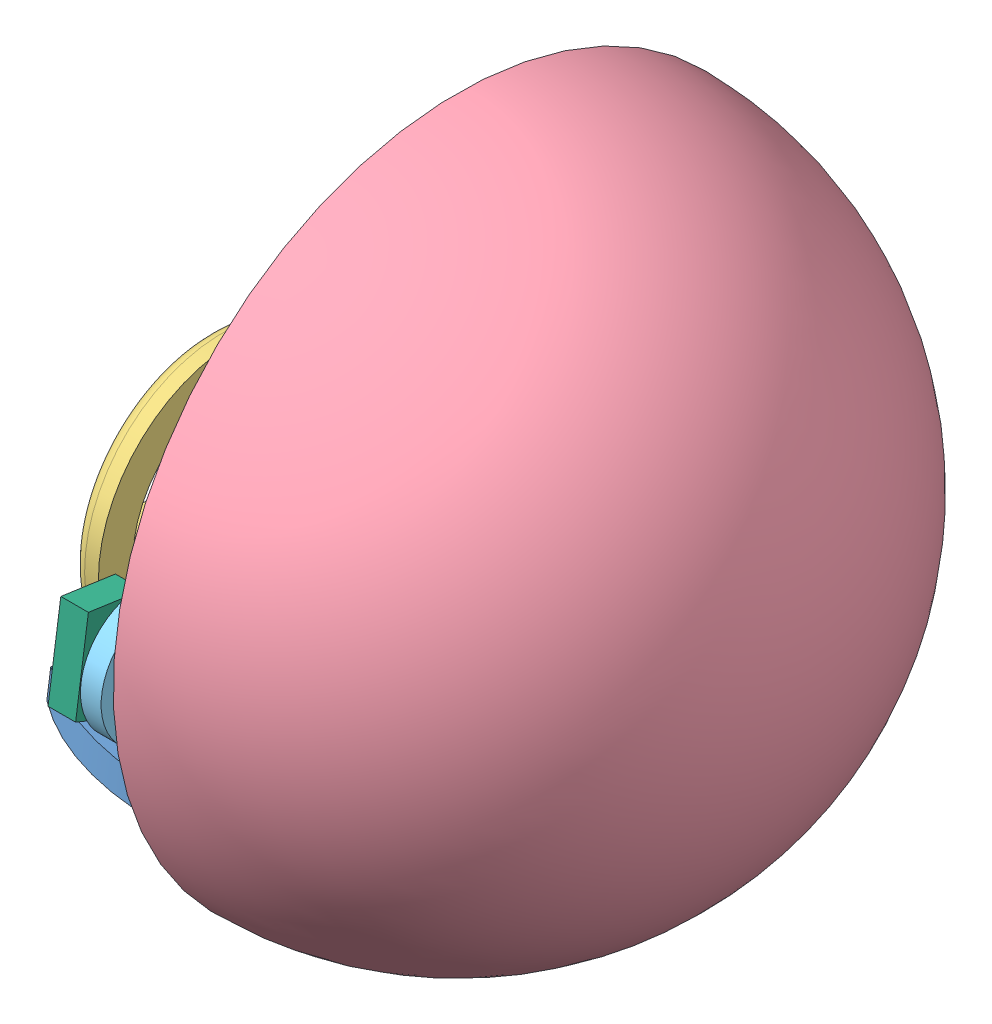
SolidWorks assembly Main, configuration Default. Lengths in mm.
Overall size (84.01 140.15 140.15).
13 component instances, 6 part files, 31 mates.
Components (placement in the parent):
- Base-1: Base [Default] at (37.3353 -161.0107 -76.7882) x (1 0 0) z (0 0.142722 0.989763) size (50 4 80)
- Motor Mount-1: Motor Mount [Default] at (15.3353 -157.0516 -77.3591) x (0 -0.142722 -0.989763) z (1 0 0) size (15.67 16 4)
- Motor Mount-2: Motor Mount [Default] at (55.3353 -157.0516 -77.3591) x (0 -0.142722 -0.989763) z (1 0 0) size (15.67 16 4)
- Wheel-1: Wheel [Default] at (67.3353 -150.1233 -78.3582) x (0 0.898799 -0.438361) z (0 -0.438361 -0.898799) size (40.79 4.01 40.79)
- Wheel-2: Wheel [Default] at (7.3353 -150.1233 -78.3582) x (0 -0.999972 -0.007423) z (0 0.007423 -0.999972) size (40.79 4.01 40.79)
- Outer Sphere-1: Outer Sphere [Default] at (37.3353 -95.9739 -49.3044) x (0 0.781433 0.62399) z (-1 0 0) size (100 100 50) (hidden)
- Outer Sphere-2: Outer Sphere [Default] at (37.3353 -174.8203 -110.8018) x (0 -0.795497 -0.605958) z (1 0 0) size (100 100 50)
- RollerLego-1: RollerLego [Default] at (28.8353 -151.7929 -114.4603) x (0 0.970228 -0.242194) z (0 -0.242194 -0.970228) size (18 17 18)
- LegoWheelMount-1: LegoWheelMount [Default] at (20.3353 -159.6392 -109.317) x (0 -0.142722 -0.989763) z (1 0 0) size (14 19 4)
- LegoWheelMount-2: LegoWheelMount [Default] at (50.3353 -159.6392 -109.317) x (0 -0.142722 -0.989763) z (1 0 0) size (14 19 4)
- LegoWheelMount-3: LegoWheelMount [Default] at (54.3353 -150.505 -45.9722) x (0 0.142722 0.989763) z (-1 0 0) size (14 19 4)
- RollerLego-2: RollerLego [Default] at (45.8353 -141.5253 -43.2551) x (0 1 0) z (0 0 1) size (18 17 18)
- LegoWheelMount-4: LegoWheelMount [Default] at (24.3353 -150.505 -45.9722) x (0 0.142722 0.989763) z (-1 0 0) size (14 19 4)
Mates (geometry in assembly coordinates):
- Coincident1: coincident anti-aligned: plane of Base-1 through (19.3353 -157.0516 -77.3591) normal (-1 0 0); plane of Motor Mount-1 through (19.3353 -157.0516 -77.3591) normal (1 0 0)
- Coincident2: coincident aligned: plane of Base-1 through (37.3353 -161.0107 -76.7882) normal (0 -0.989763 0.142722); plane of Motor Mount-1 through (19.3353 -161.0107 -76.7882) normal (0 -0.989763 0.142722)
- Coincident3: coincident anti-aligned: plane of Base-1 through (37.3353 -156.7662 -75.3796) normal (0 -0.142722 -0.989763); plane of Motor Mount-1 through (19.3353 -156.7662 -75.3796) normal (0 0.142722 0.989763)
- Coincident4: coincident anti-aligned: plane of Base-1 through (59.3353 -157.0516 -77.3591) normal (-1 0 0); plane of Motor Mount-2 through (59.3353 -157.0516 -77.3591) normal (1 0 0)
- Coincident5: coincident anti-aligned: plane of Base-1 through (37.3353 -156.7662 -75.3796) normal (0 -0.142722 -0.989763); plane of Motor Mount-2 through (59.3353 -156.7662 -75.3796) normal (0 0.142722 0.989763)
- Coincident6: coincident aligned: plane of Base-1 through (37.3353 -161.0107 -76.7882) normal (0 -0.989763 0.142722); plane of Motor Mount-2 through (59.3353 -161.0107 -76.7882) normal (0 -0.989763 0.142722)
- Concentric1: concentric aligned: circle of Motor Mount-2; circle of Wheel-1
- Concentric2: concentric anti-aligned: circle of Motor Mount-1; circle of Wheel-2
- Distance1: distance = 68 mm anti-aligned: plane of Wheel-1 through (71.3353 -150.1233 -78.3582) normal (1 0 0); plane of Wheel-2 through (3.3353 -150.1233 -78.3582) normal (-1 0 0)
- Width1: width anti-aligned: plane of Wheel-2 through (7.3353 -150.1233 -78.3582) normal (1 0 0); plane of Base-1 through (67.3353 -150.1233 -78.3582) normal (-1 0 0); plane of Wheel-1 through (12.3353 -157.0516 -77.3591) normal (-1 0 0); plane of Base-1 through (62.3353 -157.0516 -77.3591) normal (1 0 0)
- Coincident7: coincident anti-aligned: plane of Outer Sphere-1 through (37.3353 -135.0455 -80.5039) normal (1 0 0)
- Coincident8: coincident anti-aligned: plane of Outer Sphere-1 through (37.3353 -135.0455 -80.5039) normal (1 0 0); plane of Outer Sphere-2 through (37.3353 -135.0455 -80.5039) normal (-1 0 0)
- Concentric4: concentric anti-aligned: circle of Outer Sphere-1; circle of Outer Sphere-2
- Tangent1: tangent: sphere of assembly; face of Wheel-1; sphere of Outer Sphere-2
- Width2: width aligned: plane of LegoWheelMount-1 through (24.3353 -159.6392 -109.317) normal (1 0 0); plane of RollerLego-1 through (50.3353 -159.6392 -109.317) normal (-1 0 0); plane of LegoWheelMount-2 through (45.8353 -151.7929 -114.4603) normal (1 0 0); plane of RollerLego-1 through (28.8353 -151.7929 -114.4603) normal (-1 0 0)
- Coincident9: coincident anti-aligned: plane of Base-1 through (20.3353 -157.0516 -77.3591) normal (1 0 0); plane of LegoWheelMount-1 through (20.3353 -159.6392 -109.317) normal (-1 0 0)
- Coincident10: coincident anti-aligned: plane of Base-1 through (37.3353 -161.9041 -111.0111) normal (0 0.142722 0.989763); plane of LegoWheelMount-1 through (24.3353 -165.8632 -110.4402) normal (0 -0.142722 -0.989763)
- Coincident11: coincident aligned: plane of Base-1 through (37.3353 -161.0107 -76.7882) normal (0 -0.989763 0.142722); plane of LegoWheelMount-2 through (54.3353 -165.5777 -108.4607) normal (0 -0.989763 0.142722)
- Coincident12: coincident anti-aligned: plane of Base-1 through (37.3353 -161.9041 -111.0111) normal (0 0.142722 0.989763); plane of LegoWheelMount-2 through (54.3353 -165.8632 -110.4402) normal (0 -0.142722 -0.989763)
- Coincident13: coincident anti-aligned: plane of Base-1 through (50.3353 -157.0516 -77.3591) normal (1 0 0); plane of LegoWheelMount-2 through (50.3353 -159.6392 -109.317) normal (-1 0 0)
- Coincident14: coincident aligned: plane of Base-1 through (37.3353 -161.0107 -76.7882) normal (0 -0.989763 0.142722); plane of LegoWheelMount-2 through (54.3353 -165.5777 -108.4607) normal (0 -0.989763 0.142722)
- Concentric5: concentric anti-aligned: circle of RollerLego-1; circle of LegoWheelMount-2
- Coincident15: coincident aligned: plane of Base-1 through (37.3353 -161.0107 -76.7882) normal (0 -0.989763 0.142722); plane of LegoWheelMount-1 through (24.3353 -165.5777 -108.4607) normal (0 -0.989763 0.142722)
- Coincident16: coincident: plane of Base-1 through (37.3353 -152.1991 -43.7072) normal (0 -0.142722 -0.989763); plane of LegoWheelMount-3 through (50.3353 -156.1581 -43.1363) normal (0 0.142722 0.989763)
- Coincident17: coincident: plane of Base-1 through (37.3353 -161.0107 -76.7882) normal (0 -0.989763 0.142722); plane of LegoWheelMount-3 through (50.3353 -156.4436 -45.1158) normal (0 -0.989763 0.142722)
- Coincident18: coincident anti-aligned: plane of Base-1 through (54.3353 -157.0516 -77.3591) normal (-1 0 0); plane of LegoWheelMount-3 through (54.3353 -150.505 -45.9722) normal (1 0 0)
- Coincident19: coincident: plane of Base-1 through (37.3353 -153.3408 -51.6253) normal (0 0.142722 0.989763); plane of LegoWheelMount-4 through (20.3353 -151.3613 -51.9107) normal (0 -0.142722 -0.989763)
- Coincident20: coincident: plane of Base-1 through (20.3353 -157.0516 -77.3591) normal (1 0 0); plane of LegoWheelMount-4 through (20.3353 -150.505 -45.9722) normal (-1 0 0)
- Coincident21: coincident aligned: plane of Base-1 through (37.3353 -161.0107 -76.7882) normal (0 -0.989763 0.142722); plane of LegoWheelMount-4 through (20.3353 -156.4436 -45.1158) normal (0 -0.989763 0.142722)
- Concentric6: concentric: circle of LegoWheelMount-3; circle of RollerLego-2
- Width3: width anti-aligned: plane of RollerLego-2 through (28.8353 -141.5253 -43.2551) normal (-1 0 0); plane of LegoWheelMount-4 through (45.8353 -141.5253 -43.2551) normal (1 0 0); plane of RollerLego-2 through (24.3353 -150.505 -45.9722) normal (1 0 0); plane of LegoWheelMount-3 through (50.3353 -150.505 -45.9722) normal (-1 0 0)
